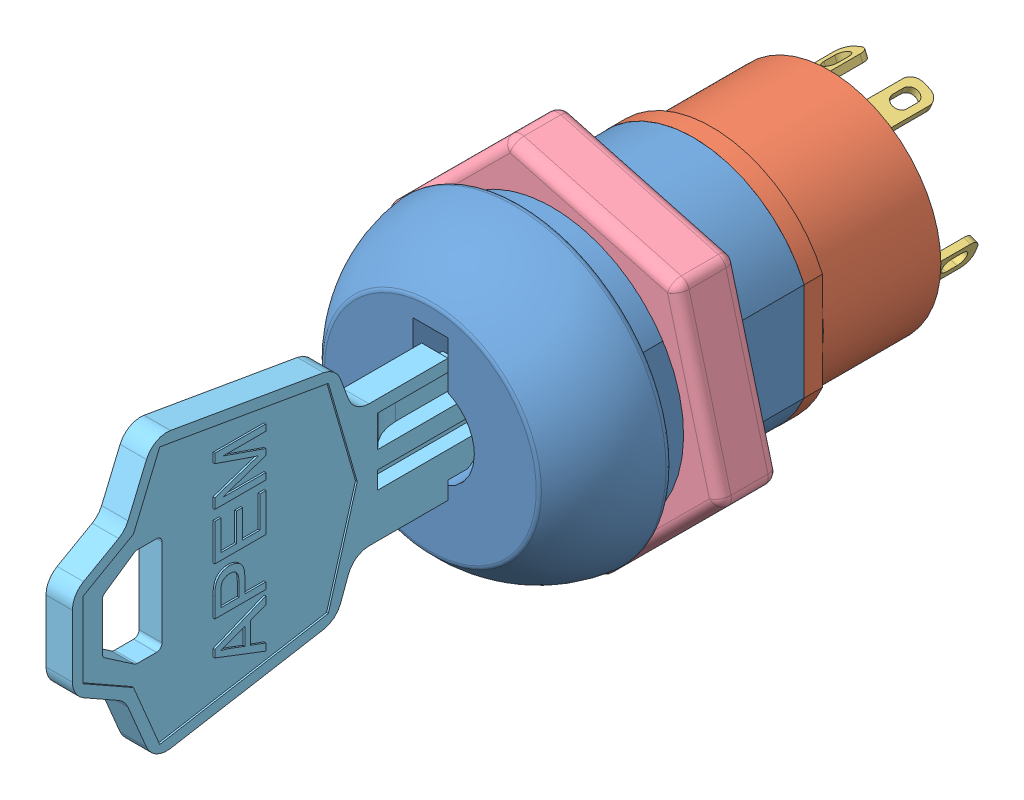
SolidWorks assembly apem-key-lock-switch, configuration Default. Lengths in mm.
Overall size (33.86 33.86 60.52).
10 component instances, 5 part files, 0 mates.
Components (placement in the parent):
- JD7509O-body-1: JD7509O-body [Default] at origin size (21.92 21.92 22.17)
- JD7509O-insert-1: JD7509O-insert [Default] at (0 0 -18.9992) size (16.13 17.5 10.9)
- JD7509O-pin-1: JD7509O-pin [Default] at (2.371 5.7811 -30.7022) x (0.92521 -0.379456 0) z (0.379456 0.92521 0) size (2.03 5.38 0.51)
- JD7509O-pin-2: JD7509O-pin [Default] at (5.7811 -2.371 -30.7022) x (-0.379456 -0.92521 0) z (0.92521 -0.379456 0) size (2.03 5.38 0.51)
- JD7509O-pin-3: JD7509O-pin [Default] at (2.4113 -5.7644 -30.7022) x (-0.922538 -0.385906 0) z (0.385906 -0.922538 0) size (2.03 5.38 0.51)
- JD7509O-pin-4: JD7509O-pin [Default] at (-2.371 -5.7811 -30.7022) x (-0.92521 0.379456 0) z (-0.379456 -0.92521 0) size (2.03 5.38 0.51)
- JD7509O-pin-5: JD7509O-pin [Default] at (-5.7811 2.371 -30.7022) x (0.379456 0.92521 0) z (-0.92521 0.379456 0) size (2.03 5.38 0.51)
- JD7509O-pin-6: JD7509O-pin [Default] at (-2.4113 5.7644 -30.7022) x (0.922538 0.385906 0) z (-0.385906 0.922538 0) size (2.03 5.38 0.51)
- JD7509O-hexnut-1: JD7509O-hexnut [Default] at (0 0 -8.7884) x (-0.707993 -0.706219 0) z (0 0 1) size (25.6 22.28 4.66)
- JD7509O-key-1: JD7509O-key [Default] at (0.3175 0.635 27.1272) x (0 -1 0) z (1 0 0) size (19.94 41.1 1.91)
